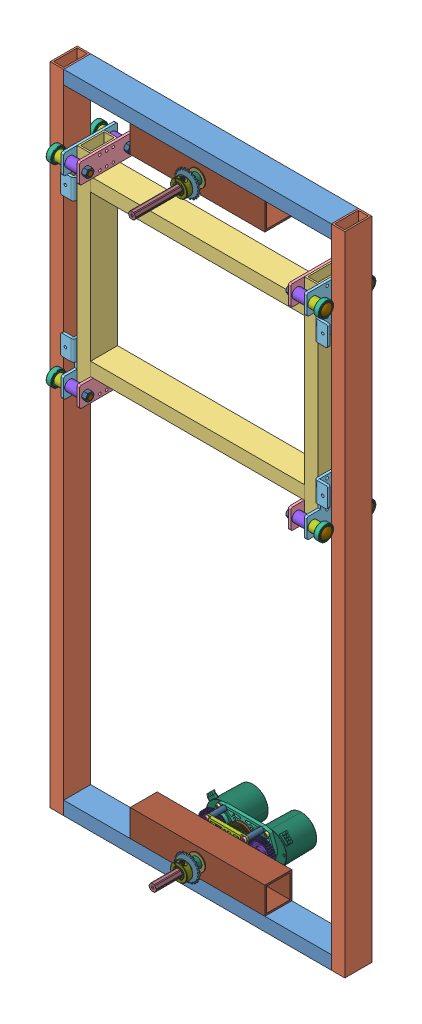
SolidWorks assembly Custom Brand New Solidwrks Assembly update, configuration Default. Lengths in mm.
Overall size (862.57 1358.12 740.13).
120 component instances, 37 part files, 54 mates.
Components (placement in the parent):
- 19 and 7 8 in extrusion-1: 19 and 7 8 in extrusion [Default] at (683.3623 192.7403 428.5412) x (-1 0 0) z (0 1 0) size (504.82 50.8 25.4)
- 2 by 1 extrusion template-1: 2 by 1 extrusion template [Default] at (153.1373 167.3403 479.3412) size (25.4 1219.2 50.8)
- 2 by 1 extrusion template-2: 2 by 1 extrusion template [Default] at (683.3623 167.3403 479.3412) size (25.4 1219.2 50.8)
- 19 and 7 8 in extrusion-2: 19 and 7 8 in extrusion [Default] at (178.5373 1361.1403 428.5412) x (1 0 0) z (0 -1 0) size (504.82 50.8 25.4)
- carrige assembly-1: carrige assembly [Default] at (190.0122 1142.6943 245.5718) x (0.837169 0.457885 -0.299148) z (0.546944 -0.700852 0.457885) size (656.01 311.13 618.97)
  - 15 7 8 height-1: 15 7 8 height [Default] at (347.2127 190.7533 277.6779) x (-0.299148 0.837169 0.457885) z (-0.457885 -0.546944 0.700852) size (50.8 403.23 25.4)
  - 15 7 8 height-2: 15 7 8 height [Default] at (397.5525 225.4843 247.0662) x (-0.299148 0.837169 0.457885) z (0.837169 0 0.546944) size (50.8 403.23 25.4)
  - 15 7 8 height-3: 15 7 8 height [Default] at (38.7209 225.4843 12.6323) x (-0.299148 0.837169 0.457885) z (0.837169 0 0.546944) size (50.8 403.23 25.4)
  - 15 7 8 height-4: 15 7 8 height [Default] at (-116.834 39.6737 250.7293) x (-0.299148 0.837169 0.457885) z (0.457885 0.546944 -0.700852) size (50.8 403.23 25.4)
  - Roller-2: Roller [Défaut] at (218.0312 36.6261 530.5498) x (-0.299148 0.837169 0.457885) z (0.457885 0.546944 -0.700852) size (108.2 74.88 88.9)
    - am3793a-1: am3793a [Défaut] at (0 -30.16 0) size (101.6 4.76 38.1)
    - am3794a-1: am3794a [Défaut] at origin size (101.6 25 88.9)
    - am-0209b-1: am-0209b [Défaut] at (-39.8145 20.6375 0) x (1 0 0) z (0 1 0) size (28.57 28.57 9.53)
    - am1451-1: am1451 [Défaut] at (-39.8145 7.9375 0) x (0 0 1) z (-1 0 0) size (19.05 15.88 19.05)
    - am1451-2: am1451 [Défaut] at (39.8145 7.9375 0) x (-1 0 0) z (0 0 -1) size (19.05 15.88 19.05)
    - am-0209b-3: am-0209b [Défaut] at (39.8145 20.6375 0) x (1 0 0) z (0 1 0) size (28.57 28.57 9.53)
    - am1450-1: am1450 [Défaut] at (-39.8145 -17.46 0) size (19.05 25.4 19.05)
    - am1450-2: am1450 [Défaut] at (39.8145 -17.46 0) size (19.05 25.4 19.05)
    - round head bolt_ai-2: round head bolt_ai [RHBOLT 0.375-16x2.75x1-C] at (-39.8145 30.4292 0) x (0 -1 0) z (-1 0 0) size (74.88 20.65 20.65)
    - round head bolt_ai-3: round head bolt_ai [RHBOLT 0.375-16x2.75x1-C] at (39.8145 30.4292 0) x (0 -1 0) z (-1 0 0) size (74.88 20.65 20.65)
    - hex nut_ai-1: hex nut_ai [HNUT 0.3750-16-D-N] at (39.8145 -43.4798 0) x (0 0 1) z (0 -1 0) size (14.27 16.48 8.56)
    - hex nut_ai-2: hex nut_ai [HNUT 0.3750-16-D-N] at (-39.8145 -43.4798 0) x (0 0 1) z (0 -1 0) size (14.27 16.48 8.56)
  - Roller-3: Roller [Défaut] at (-170.0343 36.6261 277.0166) x (0.299148 -0.837169 -0.457885) z (0.457885 0.546944 -0.700852) size (108.2 74.88 88.9)
    - am3793a-1: am3793a [Défaut] at (0 -30.16 0) size (101.6 4.76 38.1)
    - am3794a-1: am3794a [Défaut] at origin size (101.6 25 88.9)
    - am-0209b-1: am-0209b [Défaut] at (-39.8145 20.6375 0) x (1 0 0) z (0 1 0) size (28.57 28.57 9.53)
    - am1451-1: am1451 [Défaut] at (-39.8145 7.9375 0) x (0 0 1) z (-1 0 0) size (19.05 15.88 19.05)
    - am1451-2: am1451 [Défaut] at (39.8145 7.9375 0) x (-1 0 0) z (0 0 -1) size (19.05 15.88 19.05)
    - am-0209b-3: am-0209b [Défaut] at (39.8145 20.6375 0) x (1 0 0) z (0 1 0) size (28.57 28.57 9.53)
    - am1450-1: am1450 [Défaut] at (-39.8145 -17.46 0) size (19.05 25.4 19.05)
    - am1450-2: am1450 [Défaut] at (39.8145 -17.46 0) size (19.05 25.4 19.05)
    - round head bolt_ai-2: round head bolt_ai [RHBOLT 0.375-16x2.75x1-C] at (-39.8145 30.4292 0) x (0 -1 0) z (-1 0 0) size (74.88 20.65 20.65)
    - round head bolt_ai-3: round head bolt_ai [RHBOLT 0.375-16x2.75x1-C] at (39.8145 30.4292 0) x (0 -1 0) z (-1 0 0) size (74.88 20.65 20.65)
    - hex nut_ai-1: hex nut_ai [HNUT 0.3750-16-D-N] at (39.8145 -43.4798 0) x (0 0 1) z (0 -1 0) size (14.27 16.48 8.56)
    - hex nut_ai-2: hex nut_ai [HNUT 0.3750-16-D-N] at (-39.8145 -43.4798 0) x (0 0 1) z (0 -1 0) size (14.27 16.48 8.56)
  - Roller-4: Roller [Défaut] at (385.2164 236.3291 274.6512) x (0.299148 -0.837169 -0.457885) z (-0.457885 -0.546944 0.700852) size (108.2 74.88 88.9)
    - am3793a-1: am3793a [Défaut] at (0 -30.16 0) size (101.6 4.76 38.1)
    - am3794a-1: am3794a [Défaut] at origin size (101.6 25 88.9)
    - am-0209b-1: am-0209b [Défaut] at (-39.8145 20.6375 0) x (1 0 0) z (0 1 0) size (28.57 28.57 9.53)
    - am1451-1: am1451 [Défaut] at (-39.8145 7.9375 0) x (0 0 1) z (-1 0 0) size (19.05 15.88 19.05)
    - am1451-2: am1451 [Défaut] at (39.8145 7.9375 0) x (-1 0 0) z (0 0 -1) size (19.05 15.88 19.05)
    - am-0209b-3: am-0209b [Défaut] at (39.8145 20.6375 0) x (1 0 0) z (0 1 0) size (28.57 28.57 9.53)
    - am1450-1: am1450 [Défaut] at (-39.8145 -17.46 0) size (19.05 25.4 19.05)
    - am1450-2: am1450 [Défaut] at (39.8145 -17.46 0) size (19.05 25.4 19.05)
    - round head bolt_ai-2: round head bolt_ai [RHBOLT 0.375-16x2.75x1-C] at (-39.8145 30.4292 0) x (0 -1 0) z (-1 0 0) size (74.88 20.65 20.65)
    - round head bolt_ai-3: round head bolt_ai [RHBOLT 0.375-16x2.75x1-C] at (39.8145 30.4292 0) x (0 -1 0) z (-1 0 0) size (74.88 20.65 20.65)
    - hex nut_ai-1: hex nut_ai [HNUT 0.3750-16-D-N] at (39.8145 -43.4798 0) x (0 0 1) z (0 -1 0) size (14.27 16.48 8.56)
    - hex nut_ai-2: hex nut_ai [HNUT 0.3750-16-D-N] at (-39.8145 -43.4798 0) x (0 0 1) z (0 -1 0) size (14.27 16.48 8.56)
  - Roller-5: Roller [Défaut] at (-2.8492 236.3291 21.1179) x (-0.299148 0.837169 0.457885) z (-0.457885 -0.546944 0.700852) size (108.2 74.88 88.9)
    - am3793a-1: am3793a [Défaut] at (0 -30.16 0) size (101.6 4.76 38.1)
    - am3794a-1: am3794a [Défaut] at origin size (101.6 25 88.9)
    - am-0209b-1: am-0209b [Défaut] at (-39.8145 20.6375 0) x (1 0 0) z (0 1 0) size (28.57 28.57 9.53)
    - am1451-1: am1451 [Défaut] at (-39.8145 7.9375 0) x (0 0 1) z (-1 0 0) size (19.05 15.88 19.05)
    - am1451-2: am1451 [Défaut] at (39.8145 7.9375 0) x (-1 0 0) z (0 0 -1) size (19.05 15.88 19.05)
    - am-0209b-3: am-0209b [Défaut] at (39.8145 20.6375 0) x (1 0 0) z (0 1 0) size (28.57 28.57 9.53)
    - am1450-1: am1450 [Défaut] at (-39.8145 -17.46 0) size (19.05 25.4 19.05)
    - am1450-2: am1450 [Défaut] at (39.8145 -17.46 0) size (19.05 25.4 19.05)
    - round head bolt_ai-2: round head bolt_ai [RHBOLT 0.375-16x2.75x1-C] at (-39.8145 30.4292 0) x (0 -1 0) z (-1 0 0) size (74.88 20.65 20.65)
    - round head bolt_ai-3: round head bolt_ai [RHBOLT 0.375-16x2.75x1-C] at (39.8145 30.4292 0) x (0 -1 0) z (-1 0 0) size (74.88 20.65 20.65)
    - hex nut_ai-1: hex nut_ai [HNUT 0.3750-16-D-N] at (39.8145 -43.4798 0) x (0 0 1) z (0 -1 0) size (14.27 16.48 8.56)
    - hex nut_ai-2: hex nut_ai [HNUT 0.3750-16-D-N] at (-39.8145 -43.4798 0) x (0 0 1) z (0 -1 0) size (14.27 16.48 8.56)
- REV-21-2099 1-to-1-1: REV-21-2099 1-to-1 [Default] at (430.9382 218.1403 387.2662) x (0 0 1) z (-1 0 0) size (99.54 69.01 161.62)
  - REV-21-2099 1-to-1.STEP-1: REV-21-2099 1-to-1.STEP [Default] at origin size (99.54 69.01 161.62)
    - REV-21-1879_For Motor Shaft, One Clip (Spaced 0.150).STEP-1: REV-21-1879_For Motor Shaft, One Clip (Spaced 0.150).STEP [Default] at (3.5 0 45.72) x (0 0 -1) z (1 0 0) size (13 13.75 24.57)
      - REV-21-1879.STEP-1: REV-21-1879.STEP [Default] at origin size (12.7 13.75 20)
      - Key_2mm_20mmLong.STEP-1: Key_2mm_20mmLong.STEP [Default] at (0.0325 4.05 10) x (0 0 -1) z (0 1 0) size (20 2 2)
      - Retaining_Ring_8mm.STEP-1: Retaining_Ring_8mm.STEP [Default] at (0 0 24.185) x (-1 0 0) z (0 0 1) size (13 13 0.76)
    - REV-21-1879_For Motor Shaft, One Clip (Spaced 0.150).STEP-2: REV-21-1879_For Motor Shaft, One Clip (Spaced 0.150).STEP [Default] at (3.5 0 -45.72) x (0 -1 0) z (1 0 0) size (13 13.75 24.57)
      - REV-21-1879.STEP-1: REV-21-1879.STEP [Default] at origin size (12.7 13.75 20)
      - Key_2mm_20mmLong.STEP-1: Key_2mm_20mmLong.STEP [Default] at (0.0325 4.05 10) x (0 0 -1) z (0 1 0) size (20 2 2)
      - Retaining_Ring_8mm.STEP-1: Retaining_Ring_8mm.STEP [Default] at (0 0 24.185) x (-1 0 0) z (0 0 1) size (13 13 0.76)
    - REV-21-2079.STEP-1: REV-21-2079.STEP [Default] at (20.6375 0 0) size (41.27 34.92 32.55)
    - REV-21-1650.STEP-1: REV-21-1650.STEP [Default] at (0 0 -45.72) x (0 -1 0) z (1 0 0) size (65.4 64.76 93.26)
    - REV-21-1650.STEP-2: REV-21-1650.STEP [Default] at (0 0 45.72) x (0 0 -1) z (1 0 0) size (65.4 64.76 93.26)
    - REV-21-3012.STEP-1: REV-21-3012.STEP [Default] at (17.375 0 0) x (0 1 0) z (1 0 0) size (48.1 48.1 12.7)
    - REV-21-1929.STEP-1: REV-21-1929.STEP [Default] at (17.7875 0 45.72) x (0 0 1) z (-1 0 0) size (48.2 48.2 12.7)
    - REV-21-1929.STEP-2: REV-21-1929.STEP [Default] at (17.7875 0 -45.72) x (0 -0.5 0.866025) z (-1 0 0) size (48.2 48.2 12.7)
    - REV-21-2541.STEP-1: REV-21-2541.STEP [Default] at (9.4375 0 0) x (0 0 -1) z (1 0 0) size (38.1 38.1 3.17)
    - REV-21-2541.STEP-2: REV-21-2541.STEP [Default] at (25.4875 0 0) x (0 0 -1) z (1 0 0) size (38.1 38.1 3.17)
    - REV-21-2542.STEP-1: REV-21-2542.STEP [Default] at (30.25 0 0) x (0 0 1) z (-1 0 0) size (38.1 38.1 6.35)
    - F6806ZZ.STEP-1: F6806ZZ.STEP [Default] at (4.35 0 0) x (0 -0.419542 0.907736) z (-1 0 0) size (45 45 7)
    - F6806ZZ.STEP-2: F6806ZZ.STEP [Default] at (36.925 0 0) x (0 -0.734429 0.678686) z (1 0 0) size (45 45 7)
    - #10 Button Head Cap Screws_0.500 Long.STEP-1: #10 Button Head Cap Screws_0.500 Long.STEP [Default] at (1.2827 25.4 45.72) x (0 0.07794 -0.996958) z (1 0 0) size (9.17 9.17 15.27)
    - #10 Button Head Cap Screws_0.500 Long.STEP-2: #10 Button Head Cap Screws_0.500 Long.STEP [Default] at (1.2827 -25.4 45.72) x (0 0.235024 -0.971989) z (1 0 0) size (9.17 9.17 15.27)
    - #10 Button Head Cap Screws_0.500 Long.STEP-3: #10 Button Head Cap Screws_0.500 Long.STEP [Default] at (1.2827 25.4 -45.72) x (0 0.356877 -0.934151) z (1 0 0) size (9.17 9.17 15.27)
    - #10 Button Head Cap Screws_0.500 Long.STEP-4: #10 Button Head Cap Screws_0.500 Long.STEP [Default] at (1.2827 -25.4 -45.72) x (0 0.442397 -0.896819) z (1 0 0) size (9.17 9.17 15.27)
    - #10 Button Head Cap Screws_1.500 Long.STEP-1: #10 Button Head Cap Screws_1.500 Long.STEP [Default] at (20.3327 27.454 35.2002) x (0 -0.07794 0.996958) z (1 0 0) size (9.17 9.17 40.67)
    - #10 Button Head Cap Screws_1.500 Long.STEP-2: #10 Button Head Cap Screws_1.500 Long.STEP [Default] at (20.3327 27.454 -35.2002) x (0 -0.235024 0.971989) z (1 0 0) size (9.17 9.17 40.67)
    - #10 Button Head Cap Screws_1.500 Long.STEP-3: #10 Button Head Cap Screws_1.500 Long.STEP [Default] at (20.3327 -27.454 -35.2002) x (0 -0.356877 0.934151) z (1 0 0) size (9.17 9.17 40.67)
    - #10 Button Head Cap Screws_1.500 Long.STEP-4: #10 Button Head Cap Screws_1.500 Long.STEP [Default] at (20.3327 -27.454 35.2002) x (0 -0.442397 0.896819) z (1 0 0) size (9.17 9.17 40.67)
    - REV-21-2078.STEP-1: REV-21-2078.STEP [Default] at (25.725 0 45.72) x (0 0 1) z (-1 0 0) size (14.29 14.29 3.17)
    - REV-21-2078.STEP-2: REV-21-2078.STEP [Default] at (25.725 0 -45.72) x (0 1 0) z (-1 0 0) size (14.29 14.29 3.17)
    - REV-21-2099-P01.STEP-1: REV-21-2099-P01.STEP [Default] at origin size (6.35 64.43 118.43)
    - REV-21-2099-P02.STEP-1: REV-21-2099-P02.STEP [Default] at (34.925 0 0) size (6.35 64.43 79.93)
    - REV-21-2005.STEP-1: REV-21-2005.STEP [Default] at (6.675 0 45.72) x (0 0 -1) z (1 0 0) size (18.29 18.29 6.35)
    - REV-21-2003.STEP-1: REV-21-2003.STEP [Default] at (10.6438 0 45.72) x (0 0 -1) z (1 0 0) size (18.29 18.29 1.59)
    - REV-21-2003.STEP-2: REV-21-2003.STEP [Default] at (10.6438 0 -45.72) x (0 0 -1) z (1 0 0) size (18.29 18.29 1.59)
    - REV-21-2005.STEP-2: REV-21-2005.STEP [Default] at (6.675 0 -45.72) x (0 0 -1) z (1 0 0) size (18.29 18.29 6.35)
    - #10 Unthreaded Spacers_1.125in Long.STEP-1: #10 Unthreaded Spacers_1.125in Long.STEP [Default] at (20.6375 27.454 35.2002) size (28.57 9.53 9.53)
    - #10 Unthreaded Spacers_1.125in Long.STEP-2: #10 Unthreaded Spacers_1.125in Long.STEP [Default] at (20.6375 -27.454 35.2002) size (28.57 9.53 9.53)
    - #10 Unthreaded Spacers_1.125in Long.STEP-3: #10 Unthreaded Spacers_1.125in Long.STEP [Default] at (20.6375 27.454 -35.2002) size (28.57 9.53 9.53)
    - #10 Unthreaded Spacers_1.125in Long.STEP-4: #10 Unthreaded Spacers_1.125in Long.STEP [Default] at (20.6375 -27.454 -35.2002) size (28.57 9.53 9.53)
- Elevator Attachment-1: Elevator Attachment [Default] at (303.9498 243.5403 479.3412) x (1 0 0) z (0 1 0) size (254 50.8 50.8)
- Half inch flange bearing.step-1: Half inch flange bearing.step [Default] at (430.9498 218.1403 434.9445) x (-0.999907 -0.013661 0) z (0 0 -1) size (31.12 31.12 7.93)
- Half inch flange bearing.step-2: Half inch flange bearing.step [Default] at (430.9498 218.1403 472.9378) size (31.12 31.12 7.93)
- REV-half inch Hex Shaft 6.92 in-1: REV-half inch Hex Shaft 6.92 in [Default] at (430.9411 218.1453 845.3162) x (0.866025 -0.5 0) z (0 0 1) size (12.69 13.74 175.77)
- WCP-0560 Rev1.step-1: WCP-0560 Rev1.step [Default] at (430.9587 218.1149 498.3277) x (0.866025 0.5 0) z (0 0 1) size (47.96 47.68 9.53)
- WCP-0790_500L_500_hex.step-1: WCP-0790_500L_500_hex.step [Default] at (430.8649 218.0133 487.2152) x (-1 0 0) z (0 0 -1) size (19.5 19.5 12.7)
- Elevator Attachment-3: Elevator Attachment [Default] at (303.9498 1310.3403 479.3412) size (254 50.8 50.8)
- Half inch flange bearing.step-3: Half inch flange bearing.step [Default] at (430.9498 1335.7403 434.9445) x (-1 0 0) z (0 0 -1) size (31.12 31.12 7.93)
- Half inch flange bearing.step-4: Half inch flange bearing.step [Default] at (430.9498 1335.7403 472.9378) x (0.540386 0.841418 0) z (0 0 1) size (31.12 31.12 7.93)
- WCP-0560 Rev1.step-2: WCP-0560 Rev1.step [Default] at (430.9601 1335.7094 498.3277) x (-0.047279 -0.998882 0) z (0 0 1) size (47.96 47.68 9.53)
- REV-half inch Hex Shaft 6.92 in-2: REV-half inch Hex Shaft 6.92 in [Default] at (430.944 1335.7406 145.5852) x (-0.047279 -0.998882 0) z (0 0 -1) size (12.69 13.74 175.77)
- WCP-0790_500L_500_hex.step-2: WCP-0790_500L_500_hex.step [Default] at (431.0139 1335.6051 487.2152) x (-0.998882 0.047279 0) z (0 0 -1) size (19.5 19.5 12.7)
- am-1526 500Hex HD Collar Clamp.STEP-1: am-1526 500Hex HD Collar Clamp.STEP [Default] at (370.6257 292.0106 548.8001) x (-0.5 0.866025 0) z (0 0 -1) size (31.73 31.75 12.7)
  - am-1238a 500Hex Collar Clamp Body.STEP-1: am-1238a 500Hex Collar Clamp Body.STEP [Default] at (-94.2794 15.3021 33.01) size (31.73 31.75 12.7)
  - 10-32x0500_shcs_HX-SHCS 0.19-32x1.375x1-C.STEP-1: 10-32x0500_shcs_HX-SHCS 0.19-32x1.375x1-C.STEP [Default] at (-83.1669 24.154 39.36) x (0 -1 0) z (0 0 1) size (17.53 7.94 7.94)
- am-1526 500Hex HD Collar Clamp.STEP-2: am-1526 500Hex HD Collar Clamp.STEP [Default] at (374.1883 1412.3749 548.8001) x (-0.458496 0.888696 0) z (0 0 -1) size (31.73 31.75 12.7)
  - am-1238a 500Hex Collar Clamp Body.STEP-1: am-1238a 500Hex Collar Clamp Body.STEP [Default] at (-94.2794 15.3021 33.01) size (31.73 31.75 12.7)
  - 10-32x0500_shcs_HX-SHCS 0.19-32x1.375x1-C.STEP-1: 10-32x0500_shcs_HX-SHCS 0.19-32x1.375x1-C.STEP [Default] at (-83.1669 24.154 39.36) x (0 -1 0) z (0 0 1) size (17.53 7.94 7.94)
Mates (geometry in assembly coordinates):
- Coincident2: coincident aligned: plane of 19 and 7 8 in extrusion-1 through (178.5373 192.7403 479.3412) normal (0 0 1); plane of 2 by 1 extrusion template-2 through (683.3623 1386.5403 479.3412) normal (0 0 1)
- Coincident3: coincident aligned: plane of 19 and 7 8 in extrusion-1 through (178.5373 167.3403 428.5412) normal (0 -1 0); plane of 2 by 1 extrusion template-2 through (683.3623 167.3403 479.3412) normal (0 -1 0)
- Coincident4: coincident anti-aligned: plane of 19 and 7 8 in extrusion-1 through (683.3623 192.7403 428.5412) normal (1 0 0); plane of 2 by 1 extrusion template-2 through (683.3623 1386.5403 479.3412) normal (-1 0 0)
- Coincident5: coincident: plane of 19 and 7 8 in extrusion-1 through (178.5373 192.7403 479.3412) normal (0 0 1); plane of 2 by 1 extrusion template-1 through (153.1373 1386.5403 479.3412) normal (0 0 1)
- Coincident6: coincident: plane of 19 and 7 8 in extrusion-1 through (178.5373 167.3403 428.5412) normal (0 -1 0); plane of 2 by 1 extrusion template-1 through (153.1373 167.3403 479.3412) normal (0 -1 0)
- Coincident7: coincident anti-aligned: plane of 19 and 7 8 in extrusion-1 through (178.5373 192.7403 428.5412) normal (-1 0 0); plane of 2 by 1 extrusion template-1 through (178.5373 1386.5403 479.3412) normal (1 0 0)
- Coincident8: coincident anti-aligned: plane of 2 by 1 extrusion template-1 through (178.5373 1386.5403 479.3412) normal (1 0 0); plane of 19 and 7 8 in extrusion-2 through (178.5373 1361.1403 428.5412) normal (-1 0 0)
- Coincident9: coincident aligned: plane of 2 by 1 extrusion template-1 through (153.1373 1386.5403 428.5412) normal (0 0 -1); plane of 19 and 7 8 in extrusion-2 through (683.3623 1361.1403 428.5412) normal (0 0 -1)
- Coincident10: coincident aligned: plane of 2 by 1 extrusion template-2 through (683.3623 1386.5403 479.3412) normal (0 1 0); plane of 19 and 7 8 in extrusion-2 through (683.3623 1386.5403 428.5412) normal (0 1 0)
- Coincident12: coincident aligned: plane of 2 by 1 extrusion template-2 through (683.3623 1386.5403 428.5412) normal (0 0 -1); plane of carrige assembly-1/15 7 8 height-2 through (657.9623 871.673 428.5412) normal (0 0 -1)
- Width1: width aligned: plane of 2 by 1 extrusion template-2 through (683.3623 1386.5403 428.5412) normal (0 0 -1); plane of 2 by 1 extrusion template-1 through (153.1373 1386.5403 428.5412) normal (0 0 -1); plane of carrige assembly-1/15 7 8 height-2 through (657.9623 871.673 428.5412) normal (0 0 -1); plane of carrige assembly-1/15 7 8 height-3 through (229.3373 871.673 428.5412) normal (0 0 -1)
- Width2: width anti-aligned: plane of 2 by 1 extrusion template-2 through (683.3623 1386.5403 479.3412) normal (-1 0 0); plane of 2 by 1 extrusion template-1 through (178.5373 1386.5403 479.3412) normal (1 0 0); plane of carrige assembly-1/15 7 8 height-2 through (657.9623 871.673 428.5412) normal (1 0 0); plane of carrige assembly-1/15 7 8 height-3 through (203.9373 871.673 428.5412) normal (-1 0 0)
- Coincident13: coincident anti-aligned: plane of 19 and 7 8 in extrusion-1 through (178.5373 192.7403 428.5412) normal (0 1 0); plane of Elevator Attachment-1 through (557.9498 192.7403 479.3412) normal (0 -1 0)
- Coincident14: coincident aligned: plane of 19 and 7 8 in extrusion-1 through (178.5373 192.7403 428.5412) normal (0 0 -1); plane of Elevator Attachment-1 through (557.9498 243.5403 428.5412) normal (0 0 -1)
- Width3: width aligned: plane of 2 by 1 extrusion template-1 through (178.5373 1386.5403 479.3412) normal (1 0 0); plane of 2 by 1 extrusion template-2 through (683.3623 1386.5403 479.3412) normal (-1 0 0); plane of Elevator Attachment-1 through (557.9498 243.5403 479.3412) normal (1 0 0); plane of Elevator Attachment-1 through (303.9498 243.5403 479.3412) normal (-1 0 0)
- Coincident16: coincident anti-aligned: plane of Elevator Attachment-1 through (557.9498 243.5403 428.5412) normal (0 0 -1); plane of Half inch flange bearing.step-1 through (416.9811 217.9495 428.5412) normal (0 0 1)
- Concentric2: concentric aligned: cylinder of Elevator Attachment-1 through (430.9498 218.1403 83.8784) axis (0 0 1) radius 12.7; cylinder of Half inch flange bearing.step-1 through (430.9498 218.1403 427.0172) axis (0 0 1) radius 14.2875
- Concentric3: concentric anti-aligned: cylinder of Elevator Attachment-1 through (430.9498 218.1403 83.8784) axis (0 0 1) radius 12.7; cylinder of Half inch flange bearing.step-2 through (430.9498 218.1403 480.8652) axis (0 0 -1) radius 14.2875
- Coincident17: coincident anti-aligned: plane of Elevator Attachment-1 through (557.9498 243.5403 479.3412) normal (0 0 1); plane of Half inch flange bearing.step-2 through (444.9198 218.1403 479.3412) normal (0 0 -1)
- Coincident18: coincident anti-aligned: plane of REV-21-2099 1-to-1-1/REV-21-2099 1-to-1.STEP-1/REV-21-2099-P02.STEP-1 through (430.9382 218.1403 428.5412) normal (0 0 1); plane of Elevator Attachment-1 through (557.9498 243.5403 428.5412) normal (0 0 -1)
- Coincident19: coincident aligned: plane of REV-21-2099 1-to-1-1/REV-21-2099 1-to-1.STEP-1/REV-21-2079.STEP-1 through (425.8885 224.5613 388.1162) normal (0 0 -1); plane of REV-half inch Hex Shaft 6.92 in-1 through (430.9411 218.1453 388.1162) normal (0 0 -1)
- Coincident20: coincident anti-aligned: plane of REV-21-2099 1-to-1-1/REV-21-2099 1-to-1.STEP-1/REV-21-2079.STEP-1 through (438.2706 218.1403 387.2662) normal (-0.866025 -0.5 0); plane of REV-half inch Hex Shaft 6.92 in-1 through (436.4361 221.3178 1302.5162) normal (0.866025 0.5 0)
- Coincident21: coincident anti-aligned: plane of REV-21-2099 1-to-1-1/REV-21-2099 1-to-1.STEP-1/REV-21-2079.STEP-1 through (434.6044 224.4903 387.2662) normal (0 -1 0); plane of REV-half inch Hex Shaft 6.92 in-1 through (430.9411 224.4903 1302.5162) normal (0 1 0)
- Coincident23: coincident anti-aligned: plane of Half inch flange bearing.step-2 through (427.2836 224.4903 480.8652) normal (0 -1 0); plane of REV-half inch Hex Shaft 6.92 in-1 through (430.9411 224.4903 1302.5162) normal (0 1 0)
- Coincident24: coincident anti-aligned: plane of Half inch flange bearing.step-2 through (427.2836 211.7903 480.8652) normal (0.866025 0.5 0); plane of REV-half inch Hex Shaft 6.92 in-1 through (425.4462 214.9728 1302.5162) normal (-0.866025 -0.5 0)
- Parallel1: parallel aligned: plane of 19 and 7 8 in extrusion-1 through (178.5373 167.3403 428.5412) normal (0 -1 0); plane of REV-21-2099 1-to-1-1/REV-21-2099 1-to-1.STEP-1/REV-21-2099-P02.STEP-1 through (430.9382 185.9238 428.5412) normal (0 -1 0)
- Coincident42: coincident anti-aligned: plane of REV-half inch Hex Shaft 6.92 in-1 through (430.9411 224.4903 1302.5162) normal (0 1 0); plane of WCP-0790_500L_500_hex.step-1 through (427.1254 224.4903 480.8652) normal (0 -1 0)
- Coincident43: coincident anti-aligned: plane of REV-half inch Hex Shaft 6.92 in-1 through (436.4361 221.3178 1302.5162) normal (0.866025 0.5 0); plane of WCP-0790_500L_500_hex.step-1 through (434.6044 224.4903 480.8652) normal (-0.866025 -0.5 0)
- Coincident44: coincident anti-aligned: plane of Half inch flange bearing.step-2 through (446.5073 218.1403 480.8652) normal (0 0 1); plane of WCP-0790_500L_500_hex.step-1 through (430.8649 218.0133 480.8652) normal (0 0 -1)
- Coincident45: coincident anti-aligned: plane of REV-half inch Hex Shaft 6.92 in-1 through (425.4462 221.3178 1302.5162) normal (-0.866025 0.5 0); plane of WCP-0560 Rev1.step-1 through (427.2778 224.4903 493.5652) normal (0.866025 -0.5 0)
- Coincident46: coincident anti-aligned: plane of REV-half inch Hex Shaft 6.92 in-1 through (430.9411 224.4903 1302.5162) normal (0 1 0); plane of WCP-0560 Rev1.step-1 through (434.6395 224.4903 493.5652) normal (0 -1 0)
- Coincident47: coincident anti-aligned: plane of WCP-0560 Rev1.step-1 through (430.9587 218.1149 493.5652) normal (0 0 -1); plane of WCP-0790_500L_500_hex.step-1 through (430.8649 218.0133 493.5652) normal (0 0 1)
- Coincident48: coincident anti-aligned: plane of 19 and 7 8 in extrusion-2 through (683.3623 1361.1403 428.5412) normal (0 -1 0); plane of Elevator Attachment-3 through (557.9498 1361.1403 479.3412) normal (0 1 0)
- Coincident49: coincident aligned: plane of 19 and 7 8 in extrusion-2 through (683.3623 1361.1403 428.5412) normal (0 0 -1); plane of Elevator Attachment-3 through (557.9498 1310.3403 428.5412) normal (0 0 -1)
- Width6: width anti-aligned: plane of 2 by 1 extrusion template-1 through (178.5373 1386.5403 479.3412) normal (1 0 0); plane of 2 by 1 extrusion template-2 through (683.3623 1386.5403 479.3412) normal (-1 0 0); plane of Elevator Attachment-3 through (303.9498 1310.3403 479.3412) normal (-1 0 0); plane of Elevator Attachment-3 through (557.9498 1310.3403 479.3412) normal (1 0 0)
- Coincident50: coincident anti-aligned: plane of Elevator Attachment-3 through (557.9498 1310.3403 428.5412) normal (0 0 -1); plane of Half inch flange bearing.step-3 through (416.9798 1335.7403 428.5412) normal (0 0 1)
- Concentric4: concentric anti-aligned: cylinder of Elevator Attachment-3 through (430.9498 1335.7403 824.0039) axis (0 0 -1) radius 12.7; cylinder of Half inch flange bearing.step-3 through (430.9498 1335.7403 427.0172) axis (0 0 1) radius 14.2875
- Coincident51: coincident anti-aligned: plane of Elevator Attachment-3 through (557.9498 1310.3403 479.3412) normal (0 0 1); plane of Half inch flange bearing.step-4 through (438.499 1347.4949 479.3412) normal (0 0 -1)
- Concentric5: concentric aligned: cylinder of Elevator Attachment-3 through (430.9498 1335.7403 824.0039) axis (0 0 -1) radius 12.7; cylinder of Half inch flange bearing.step-4 through (430.9498 1335.7403 480.8652) axis (0 0 -1) radius 14.2875
- Distance1: distance = 0 mm aligned: plane of REV-half inch Hex Shaft 6.92 in-2 through (428.6501 1287.2759 427.0172) normal (0 0 -1); plane of Half inch flange bearing.step-3 through (415.3923 1335.7403 427.0172) normal (0 0 -1)
- Coincident53: coincident anti-aligned: plane of Half inch flange bearing.step-4 through (426.9875 1329.5708 480.8652) normal (0.888696 0.458496 0); plane of REV-half inch Hex Shaft 6.92 in-2 through (425.3052 1332.8314 -311.6148) normal (-0.888696 -0.458496 0)
- Coincident54: coincident anti-aligned: plane of Half inch flange bearing.step-4 through (423.6256 1336.087 480.8652) normal (0.841418 -0.540386 0); plane of REV-half inch Hex Shaft 6.92 in-2 through (425.6052 1339.1693 -311.6148) normal (-0.841418 0.540386 0)
- Coincident55: coincident anti-aligned: plane of Half inch flange bearing.step-4 through (439.3568 1348.8307 480.8652) normal (0 0 1); plane of WCP-0790_500L_500_hex.step-2 through (431.0139 1335.6051 480.8652) normal (0 0 -1)
- Coincident56: coincident anti-aligned: plane of REV-half inch Hex Shaft 6.92 in-2 through (431.244 1342.0785 -311.6148) normal (0.047279 0.998882 0); plane of WCP-0790_500L_500_hex.step-2 through (427.5848 1342.2517 480.8652) normal (-0.047279 -0.998882 0)
- Coincident57: coincident anti-aligned: plane of REV-half inch Hex Shaft 6.92 in-2 through (425.6052 1339.1693 -311.6148) normal (-0.841418 0.540386 0); plane of WCP-0790_500L_500_hex.step-2 through (423.5433 1335.9587 480.8652) normal (0.841418 -0.540386 0)
- Coincident58: coincident anti-aligned: plane of WCP-0560 Rev1.step-2 through (430.9601 1335.7094 493.5652) normal (0 0 -1); plane of WCP-0790_500L_500_hex.step-2 through (431.0139 1335.6051 493.5652) normal (0 0 1)
- Coincident59: coincident anti-aligned: plane of WCP-0560 Rev1.step-2 through (434.9383 1341.9036 493.5652) normal (-0.047279 -0.998882 0); plane of REV-half inch Hex Shaft 6.92 in-2 through (431.244 1342.0785 -311.6148) normal (0.047279 0.998882 0)
- Coincident60: coincident anti-aligned: plane of WCP-0560 Rev1.step-2 through (427.5848 1342.2517 493.5652) normal (0.841418 -0.540386 0); plane of REV-half inch Hex Shaft 6.92 in-2 through (425.6052 1339.1693 -311.6148) normal (-0.841418 0.540386 0)
- Coincident61: coincident anti-aligned: plane of WCP-0560 Rev1.step-1 through (430.9587 218.1149 503.0902) normal (0 0 1); plane of am-1526 500Hex HD Collar Clamp.STEP-1/am-1238a 500Hex Collar Clamp Body.STEP-1 through (431.0173 218.0133 503.0902) normal (0 0 -1)
- Coincident62: coincident anti-aligned: plane of REV-half inch Hex Shaft 6.92 in-1 through (430.9411 224.4903 1302.5162) normal (0 1 0); plane of am-1526 500Hex HD Collar Clamp.STEP-1/am-1238a 500Hex Collar Clamp Body.STEP-1 through (427.2778 224.4903 515.7902) normal (0 -1 0)
- Coincident63: coincident anti-aligned: plane of REV-half inch Hex Shaft 6.92 in-1 through (425.4462 221.3178 1302.5162) normal (-0.866025 0.5 0); plane of am-1526 500Hex HD Collar Clamp.STEP-1/am-1238a 500Hex Collar Clamp Body.STEP-1 through (423.5383 218.0133 515.7902) normal (0.866025 -0.5 0)
- Coincident64: coincident anti-aligned: plane of WCP-0560 Rev1.step-2 through (430.9601 1335.7094 503.0902) normal (0 0 1); plane of am-1526 500Hex HD Collar Clamp.STEP-2/am-1238a 500Hex Collar Clamp Body.STEP-1 through (431.0139 1335.6051 503.0902) normal (0 0 -1)
- Coincident65: coincident anti-aligned: plane of REV-half inch Hex Shaft 6.92 in-2 through (431.244 1342.0785 -311.6148) normal (0.047279 0.998882 0); plane of am-1526 500Hex HD Collar Clamp.STEP-2/am-1238a 500Hex Collar Clamp Body.STEP-1 through (427.5848 1342.2517 515.7902) normal (-0.047279 -0.998882 0)
- Coincident66: coincident anti-aligned: plane of REV-half inch Hex Shaft 6.92 in-2 through (425.6052 1339.1693 -311.6148) normal (-0.841418 0.540386 0); plane of am-1526 500Hex HD Collar Clamp.STEP-2/am-1238a 500Hex Collar Clamp Body.STEP-1 through (423.5433 1335.9587 515.7902) normal (0.841418 -0.540386 0)
